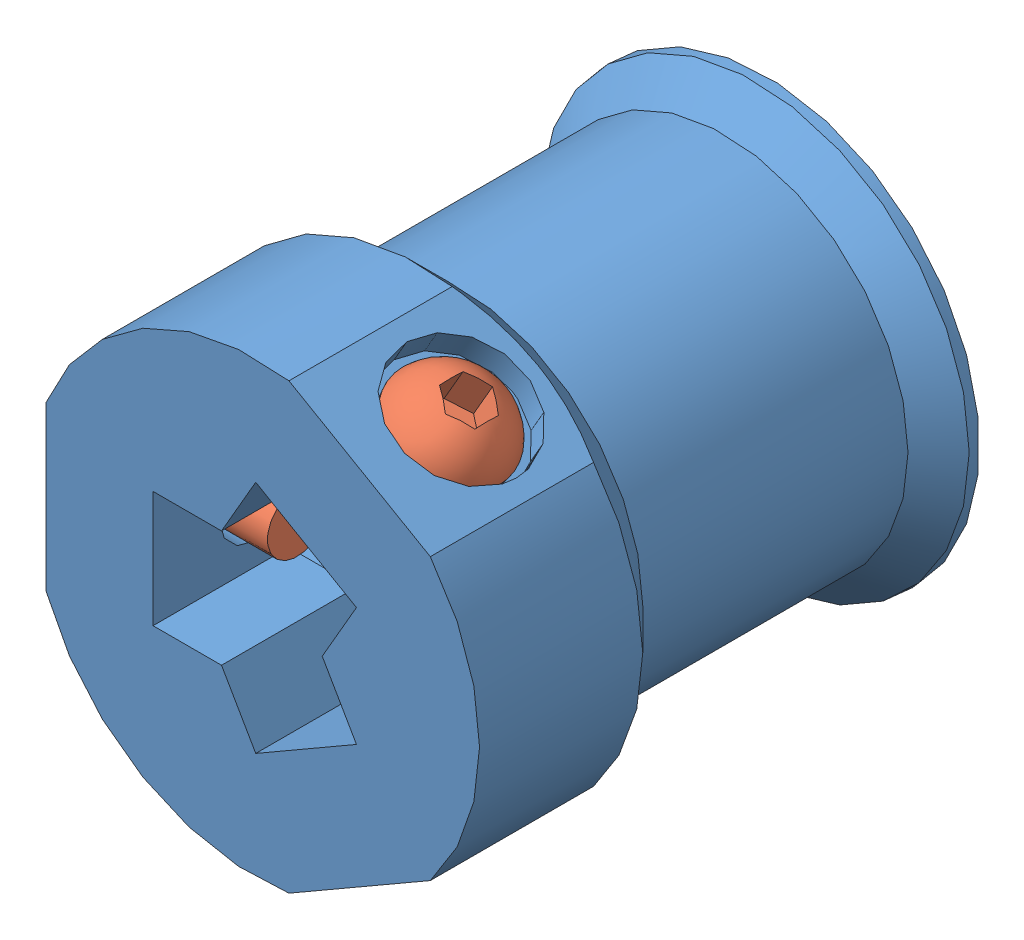
SolidWorks assembly Spool and Screws, configuration Default. Lengths in mm.
Overall size (21.92 22 25).
4 component instances, 2 part files, 2 mates.
Components (placement in the parent):
- Spool-1: Spool [Default] at origin size (21.5 22 25)
- Button Head Screw-1: Button Head Screw [M3 x 6] at (-3 0 19.9458) x (0 0 1) z (-1 0 0) size (5.4 5.4 7.92)
- Button Head Screw-2: Button Head Screw [M3 x 6] at (1.5 -2.5981 19.9458) x (0 0 1) z (0.5 -0.866025 0) size (5.4 5.4 7.92)
- Button Head Screw-3: Button Head Screw [M3 x 6] at (1.5 2.5981 19.9458) x (0 0 1) z (0.5 0.866025 0) size (5.4 5.4 7.92)
Mates (geometry in assembly coordinates):
- Distance1: distance = 1 mm anti-aligned: plane of Spool-1 through (-8 0 20) normal (-1 0 0); plane of Button Head Screw-1 through (-9 0 19.9458) normal (1 0 0)
- Coincident2: coincident aligned: plane of Button Head Screw-1; plane of assembly through (0 0 0) normal (0 1 0)
